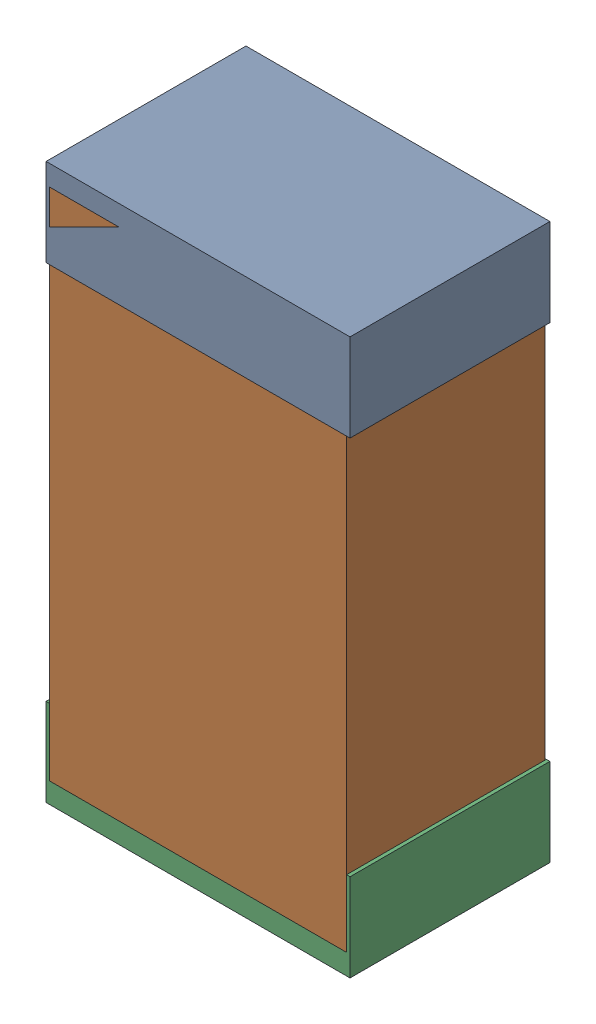
SolidWorks assembly R32Kanaloa_v2.0.0_Motor, configuration Default. Lengths in mm.
Overall size (1.3 2.38 0.85).
6 component instances, 2 part files, 0 mates.
Components (placement in the parent):
- 330415056-1: 330415056 [Default] at (124.714 100.568 -1.9574) size (1.3 0.38 0.85)
  - Extruded_2-1: Extruded_2 [Default] at origin size (1.3 0.38 0.85)
- 334787376-1: 334787376 [Default] at (124.714 99.568 -1.9524) size (1.27 2.2 0.85)
  - Extruded_16-1: Extruded_16 [Default] at origin size (1.27 2.2 0.85)
- 330415056-2: 330415056 [Default] at (124.714 98.568 -1.9574) size (1.3 0.38 0.85)
  - Extruded_2-1: Extruded_2 [Default] at origin size (1.3 0.38 0.85)
